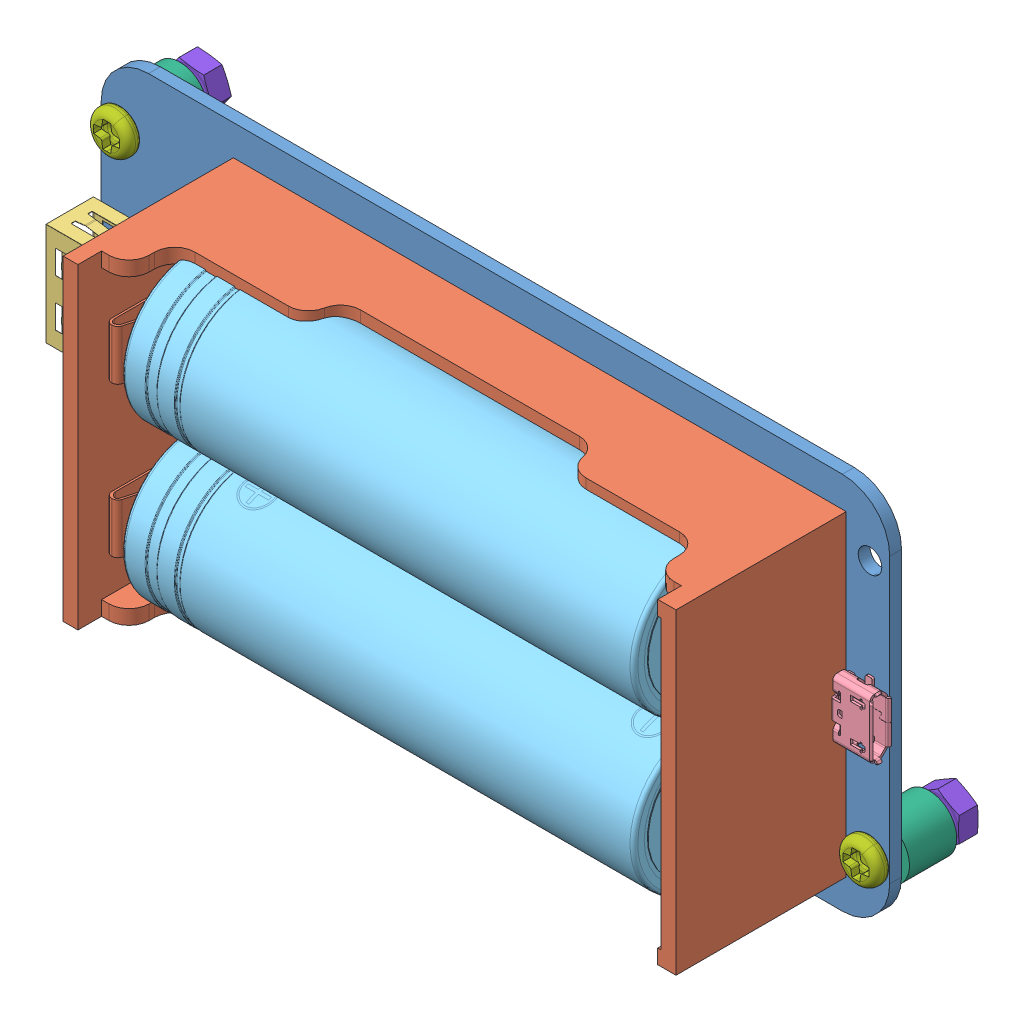
SolidWorks assembly DP, configuration Predeterminado. Lengths in mm.
Overall size (102.94 48 33.9).
15 component instances, 8 part files, 36 mates.
Components (placement in the parent):
- 18650_Battery Holder_PCB-1: 18650_Battery Holder_PCB [Predeterminado] at (4.2336 3.5444 100) size (100 48 1.5)
- 18650_Battery Holder-1: 18650_Battery Holder [Predeterminado] at (15.2659 0.4104 101.5) x (1 0 0) z (0 -1 0) size (77.72 24.77 40.13)
- USB Typ A Buchse-1: USB Typ A Buchse [Predeterminado] at (-22.3556 8.2697 102.5) x (-1 0 0) z (0 0 1) size (17 15.6 7.7)
- micro_usb-1: micro_usb [Predeterminado] at (57.3509 0.2464 101.3932) x (0 1 0) z (1 0 0) size (7.98 2.76 5.43)
- 18650-1: 18650 [Default] at (47.6086 10.1819 112.7066) x (0 0.035864 -0.999357) z (0 0.999357 0.035864) size (18.4 65 18.4)
- 18650-2: 18650 [Default] at (47.6086 -9.3611 112.7066) x (0 0.951827 0.306637) z (0 -0.306637 0.951827) size (18.4 65 18.4)
- separador-2: separador [Predeterminado] at (-37.8556 16.5944 94) x (0.999851 0.017264 0) z (0 0 1) size (7 7 6)
- separador-3: separador [Predeterminado] at (57.1444 -15.9056 94) x (0.994584 0.103934 0) z (0 0 1) size (7 7 6)
- M3x10 Philips Screw-2: M3x10 Philips Screw [Predeterminado] at (57.1444 -15.9056 101.5) size (5.3 5.3 11.8)
- M3x10 Philips Screw-3: M3x10 Philips Screw [Predeterminado] at (-37.8556 16.5944 101.5) size (5.3 5.3 11.8)
- M3 Nut-2: M3 Nut [Predeterminado] at (-37.8556 16.5944 89) x (-0.923728 -0.383049 0) z (0 0 -1) size (6.27 6.27 2.71)
- M3 Nut-3: M3 Nut [Predeterminado] at (57.1444 -15.9056 94.5) size (6.27 6.27 2.71)
- separador-4: separador [Predeterminado] at (-37.8556 -15.9056 94) size (7 7 6)
- M3x10 Philips Screw-4: M3x10 Philips Screw [Predeterminado] at (-37.8556 -15.9056 101.5) x (0.99234 0.123538 0) z (0 0 1) size (5.3 5.3 11.8)
- M3 Nut-4: M3 Nut [Predeterminado] at (-37.8556 -15.9056 94.5) size (6.27 6.27 2.71)
Mates (geometry in assembly coordinates):
- Coincidente1: coincident: plane of 18650_Battery Holder_PCB-1 through (53.6444 18.3444 101.5) normal (0 0 1); plane of 18650_Battery Holder-1 through (15.2659 0.4104 101.5) normal (0 0 -1)
- Distancia2: distance = 0.1 mm: plane of micro_usb-1 through (55.4709 -14.0274 101.6) normal (0 0 -1); plane of 18650_Battery Holder_PCB-1 through (53.6444 18.3444 101.5) normal (0 0 1)
- Paralelo2: parallel: plane of 18650_Battery Holder_PCB-1 through (-40.3556 -17.6556 101.5) normal (-1 0 0); plane of micro_usb-1 through (54.5009 6.001 104.4784) normal (-1 0 0)
- Coincidente6: coincident: plane of 18650_Battery Holder_PCB-1 through (53.6444 18.3444 101.5) normal (0 0 1); plane of USB Typ A Buchse-1 through (-27.3556 7.8697 101.5) normal (0 0 -1)
- Paralelo4: parallel: plane of 18650_Battery Holder_PCB-1 through (53.6444 -23.6556 101.5) normal (0 -1 0); plane of USB Typ A Buchse-1 through (-26.3556 -4.7303 102.5) normal (0 -1 0)
- Coincidente8: coincident: plane of 18650_Battery Holder_PCB-1 through (-40.3556 -17.6556 101.5) normal (-1 0 0); plane of USB Typ A Buchse-1 through (-40.3556 1.7848 105.4949) normal (-1 0 0)
- Bloquear1: lock: unknown of 18650_Battery Holder_PCB-1; unknown of USB Typ A Buchse-1
- Tangente3: tangent: plane of 18650_Battery Holder-1 through (15.2659 0.4104 103.5066) normal (0 0 1); cylinder of 18650-1 through (47.6086 10.1819 112.7066) axis (-1 0 0) radius 9.2
- Tangente4: tangent: plane of 18650_Battery Holder-1 through (-21.7165 0.9819 113.438) normal (0 1 0); cylinder of 18650-1 through (47.6086 10.1819 112.7066) axis (-1 0 0) radius 9.2
- Tangente5: tangent: plane of 18650_Battery Holder-1 through (15.2659 0.4104 103.5066) normal (0 0 1); cylinder of 18650-2 through (47.6086 -9.3611 112.7066) axis (-1 0 0) radius 9.2
- Tangente6: tangent: plane of 18650_Battery Holder-1 through (52.2483 -0.1611 113.438) normal (0 -1 0); cylinder of 18650-2 through (47.6086 -9.3611 112.7066) axis (-1 0 0) radius 9.2
- Coincidente11: coincident: plane of 18650-1 through (47.6086 10.1819 112.7066) normal (1 0 0); plane of 18650-2 through (47.6086 -9.3611 112.7066) normal (1 0 0)
- Concéntrica1: concentric: circle of 18650_Battery Holder_PCB-1; circle of separador-3
- Concéntrica2: concentric: circle of 18650_Battery Holder_PCB-1; circle of ?
- Concéntrica3: concentric: circle of 18650_Battery Holder_PCB-1; circle of separador-2
- Coincidente12: coincident: plane of 18650_Battery Holder_PCB-1 through (53.6444 18.3444 100) normal (0 0 -1); plane of ? through (-37.8556 -15.9056 100) normal (0 0 1)
- Coincidente13: coincident: plane of 18650_Battery Holder_PCB-1 through (53.6444 18.3444 100) normal (0 0 -1); plane of separador-2 through (-37.8556 16.5944 100) normal (0 0 1)
- Coincidente14: coincident: plane of 18650_Battery Holder_PCB-1 through (53.6444 18.3444 100) normal (0 0 -1); plane of separador-3 through (57.1444 -15.9056 100) normal (0 0 1)
- Coincidente15: coincident: plane of 18650_Battery Holder_PCB-1 through (53.6444 18.3444 101.5) normal (0 0 1); plane of ? through (-37.8556 -14.3056 101.5) normal (0 0 -1)
- Concéntrica4: concentric: circle of 18650_Battery Holder_PCB-1; circle of ?
- Coincidente16: coincident: plane of 18650_Battery Holder_PCB-1 through (53.6444 18.3444 101.5) normal (0 0 1); plane of M3x10 Philips Screw-2 through (57.1444 -14.3056 101.5) normal (0 0 -1)
- Concéntrica5: concentric: circle of 18650_Battery Holder_PCB-1; circle of M3x10 Philips Screw-2
- Coincidente17: coincident: plane of 18650_Battery Holder_PCB-1 through (53.6444 18.3444 101.5) normal (0 0 1); plane of M3x10 Philips Screw-3 through (-37.8556 18.1944 101.5) normal (0 0 -1)
- Concéntrica6: concentric: circle of 18650_Battery Holder_PCB-1; circle of M3x10 Philips Screw-3
- Distancia3: distance = 1 mm: plane of separador-3 through (57.1444 -15.9056 94) normal (0 0 -1); plane of M3 Nut-3 through (57.1444 -15.9056 93) normal (0 0 1)
- Concéntrica7: concentric: circle of separador-3; circle of M3 Nut-3
- Distancia4: distance = 1 mm: plane of ? through (-37.8556 -15.9056 94) normal (0 0 -1); plane of ? through (-37.8556 -15.9056 93) normal (0 0 1)
- Concéntrica8: concentric: circle of ?; circle of ?
- Distancia5: distance = 1 mm: plane of separador-2 through (-37.8556 16.5944 94) normal (0 0 -1); plane of M3 Nut-2 through (-37.8556 16.5944 93) normal (0 0 1)
- Concéntrica9: concentric: circle of separador-2; circle of M3 Nut-2
- Coincidente18: coincident: plane of 18650_Battery Holder_PCB-1 through (53.6444 18.3444 100) normal (0 0 -1); plane of separador-4 through (-37.8556 -15.9056 100) normal (0 0 1)
- Concéntrica10: concentric: circle of 18650_Battery Holder_PCB-1; circle of separador-4
- Concéntrica11: concentric: circle of 18650_Battery Holder_PCB-1; circle of M3x10 Philips Screw-4
- Coincidente19: coincident: plane of 18650_Battery Holder_PCB-1 through (53.6444 18.3444 101.5) normal (0 0 1); plane of M3x10 Philips Screw-4 through (-38.0533 -14.3178 101.5) normal (0 0 -1)
- Distancia6: distance = 1 mm: plane of M3 Nut-4 through (-37.8556 -15.9056 93) normal (0 0 1); plane of separador-4 through (-37.8556 -15.9056 94) normal (0 0 -1)
- Concéntrica12: concentric: circle of separador-4; circle of M3 Nut-4
